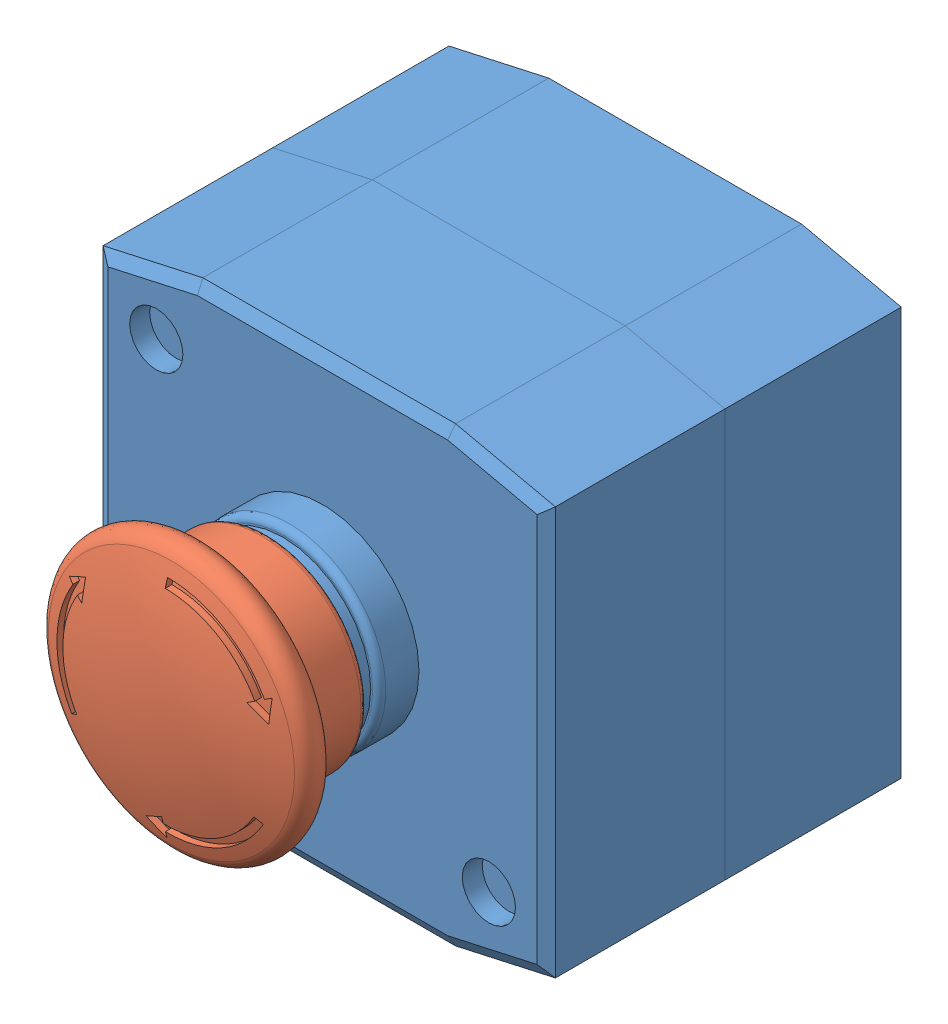
SolidWorks assembly E-Stop, configuration Engaged. Lengths in mm.
Overall size (68 68 78.72).
2 component instances, 2 part files, 2 mates.
Components (placement in the parent):
- E-Stop-2: E-Stop [Default] at (63.4505 9.588 -45.9739)
- E-Stop Red Mushroom-1: E-Stop Red Mushroom [Default] at (63.4505 9.588 -58.2553)
Mates (geometry in assembly coordinates):
- Concentric1: concentric anti-aligned: circle of E-Stop Red Mushroom-1; circle of E-Stop-2
- Coincident2: coincident anti-aligned: plane of E-Stop Red Mushroom-1 through (63.4505 43.588 27.5261) normal (0 0 -1); plane of E-Stop-2 through (63.4505 43.588 27.5261) normal (0 0 1)
